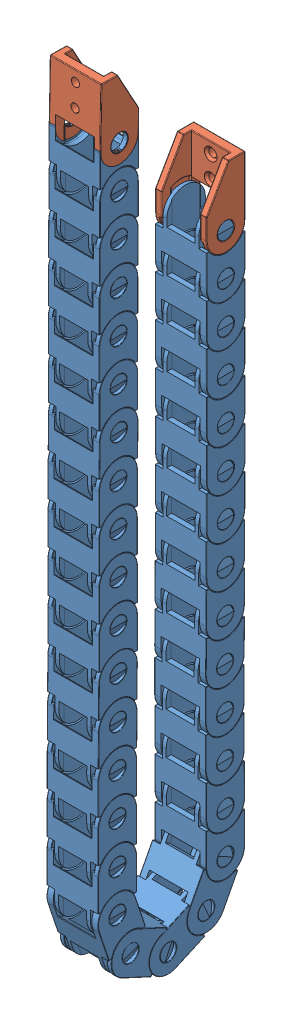
SolidWorks assembly CableChain, configuration Valor predeterminado. Lengths in mm.
Overall size (18.81 294.87 57.67).
35 component instances, 2 part files, 0 mates.
Components (placement in the parent):
- esteira 15mm meio-1: esteira 15mm meio [Valor predeterminado] at (-22.3167 -385.4947 64.2503) x (-1 0 0) z (0 0.317305 -0.948324) size (18.71 29.17 14)
- esteira 15mm ponta-1: esteira 15mm ponta [Valor predeterminado] at (-22.318 -173.1904 13.4249) x (-1 0 0) z (0 0 1) size (18.71 28.52 14)
- esteira 15mm meio-2: esteira 15mm meio [Valor predeterminado] at (-22.3387 -388.0033 37.6001) x (1 0 0) z (0 -0.913545 -0.406737) size (18.71 29.17 14)
- esteira 15mm meio-3: esteira 15mm meio [Valor predeterminado] at (-22.3146 -249.0126 27.4078) x (1 0 0) z (0 0 -1) size (18.71 29.17 14)
- esteira 15mm meio-4: esteira 15mm meio [Valor predeterminado] at (-22.3271 -324.9133 27.7164) x (1 0 0) z (0 0 -1) size (18.71 29.17 14)
- esteira 15mm meio-5: esteira 15mm meio [Valor predeterminado] at (-22.3222 -381.4774 30.4113) x (1 0 0) z (0 -0.461749 -0.887011) size (18.71 29.17 14)
- esteira 15mm meio-6: esteira 15mm meio [Valor predeterminado] at (-22.334 -355.3333 27.6189) x (1 0 0) z (0 0.008727 -0.999962) size (18.71 29.17 14)
- esteira 15mm meio-7: esteira 15mm meio [Valor predeterminado] at (-22.3341 -387.6186 45.5345) x (1 0 0) z (0 -0.906308 0.422618) size (18.71 29.17 14)
- esteira 15mm meio-8: esteira 15mm meio [Valor predeterminado] at (-22.3247 -322.9926 52.7684) x (1 0 0) z (0 0.008727 0.999962) size (18.71 29.17 14)
- esteira 15mm meio-9: esteira 15mm meio [Valor predeterminado] at (-22.3384 -307.7895 52.6373) x (1 0 0) z (0 0.008727 0.999962) size (18.71 29.17 14)
- esteira 15mm meio-11: esteira 15mm meio [Valor predeterminado] at (-22.3209 -262.1913 52.5803) size (18.71 29.17 14)
- esteira 15mm meio-12: esteira 15mm meio [Valor predeterminado] at (-22.3466 -231.8827 52.4074) x (1 0 0) z (0 0.008727 0.999962) size (18.71 29.17 14)
- esteira 15mm meio-13: esteira 15mm meio [Valor predeterminado] at (-22.3232 -368.5059 52.8569) size (18.71 29.17 14)
- esteira 15mm meio-14: esteira 15mm meio [Valor predeterminado] at (-22.324 -277.3762 52.553) size (18.71 29.17 14)
- esteira 15mm meio-15: esteira 15mm meio [Valor predeterminado] at (-22.3388 -201.4377 52.4327) size (18.71 29.17 14)
- esteira 15mm meio-16: esteira 15mm meio [Valor predeterminado] at (-22.3225 -353.3076 52.8596) size (18.71 29.17 14)
- esteira 15mm meio-17: esteira 15mm meio [Valor predeterminado] at (-22.3279 -247.0151 52.5574) size (18.71 29.17 14)
- esteira 15mm meio-18: esteira 15mm meio [Valor predeterminado] at (-22.3256 -292.5631 52.5622) size (18.71 29.17 14)
- esteira 15mm meio-19: esteira 15mm meio [Valor predeterminado] at (-22.3305 -216.6139 52.4266) size (18.71 29.17 14)
- esteira 15mm meio-20: esteira 15mm meio [Valor predeterminado] at (-22.3221 -171.0879 52.3443) x (1 0 0) z (0 0.008727 0.999962) size (18.71 29.17 14)
- esteira 15mm meio-21: esteira 15mm meio [Valor predeterminado] at (-22.3231 -186.249 52.4208) size (18.71 29.17 14)
- esteira 15mm meio-22: esteira 15mm meio [Valor predeterminado] at (-22.322 -338.1238 52.8394) size (18.71 29.17 14)
- esteira 15mm meio-25: esteira 15mm meio [Valor predeterminado] at (-22.3119 -340.0523 27.7115) x (1 0 0) z (0 0 -1) size (18.71 29.17 14)
- esteira 15mm meio-27: esteira 15mm meio [Valor predeterminado] at (-22.3231 -140.6384 52.1621) size (18.71 29.17 14)
- esteira 15mm meio-29: esteira 15mm meio [Valor predeterminado] at (-22.3273 -155.8576 52.2339) size (18.71 29.17 14)
- esteira 15mm meio-30: esteira 15mm meio [Valor predeterminado] at (-22.3109 -309.6566 27.6571) x (1 0 0) z (0 -0.008727 -0.999962) size (18.71 29.17 14)
- esteira 15mm meio-31: esteira 15mm meio [Valor predeterminado] at (-22.3151 -370.4492 27.5827) x (1 0 0) z (0 0 -1) size (18.71 29.17 14)
- esteira 15mm meio-32: esteira 15mm meio [Valor predeterminado] at (-22.4083 -279.3752 27.4303) x (1 0 0) z (0 0 -1) size (18.71 29.17 14)
- esteira 15mm meio-33: esteira 15mm meio [Valor predeterminado] at (-22.3793 -218.647 27.418) x (1 0 0) z (0 0 -1) size (18.71 29.17 14)
- esteira 15mm meio-35: esteira 15mm meio [Valor predeterminado] at (-22.3359 -233.829 27.4223) x (1 0 0) z (0 0 -1) size (18.71 29.17 14)
- esteira 15mm meio-36: esteira 15mm meio [Valor predeterminado] at (-22.3849 -294.5033 27.5145) x (1 0 0) z (0 -0.008727 -0.999962) size (18.71 29.17 14)
- esteira 15mm meio-37: esteira 15mm meio [Valor predeterminado] at (-22.3863 -264.2052 27.4154) x (1 0 0) z (0 0 -1) size (18.71 29.17 14)
- esteira 15mm meio-39: esteira 15mm meio [Valor predeterminado] at (-22.318 -188.3174 27.4462) x (1 0 0) z (0 0 -1) size (18.71 29.17 14)
- esteira 15mm meio-40: esteira 15mm meio [Valor predeterminado] at (-22.3238 -203.4893 27.433) x (1 0 0) z (0 0 -1) size (18.71 29.17 14)
- esteira 15mm ponta-2: esteira 15mm ponta [Valor predeterminado] at (-22.3155 -125.9961 66.0136) x (1 0 0) z (0 -0.017452 -0.999848) size (18.71 28.52 14)
